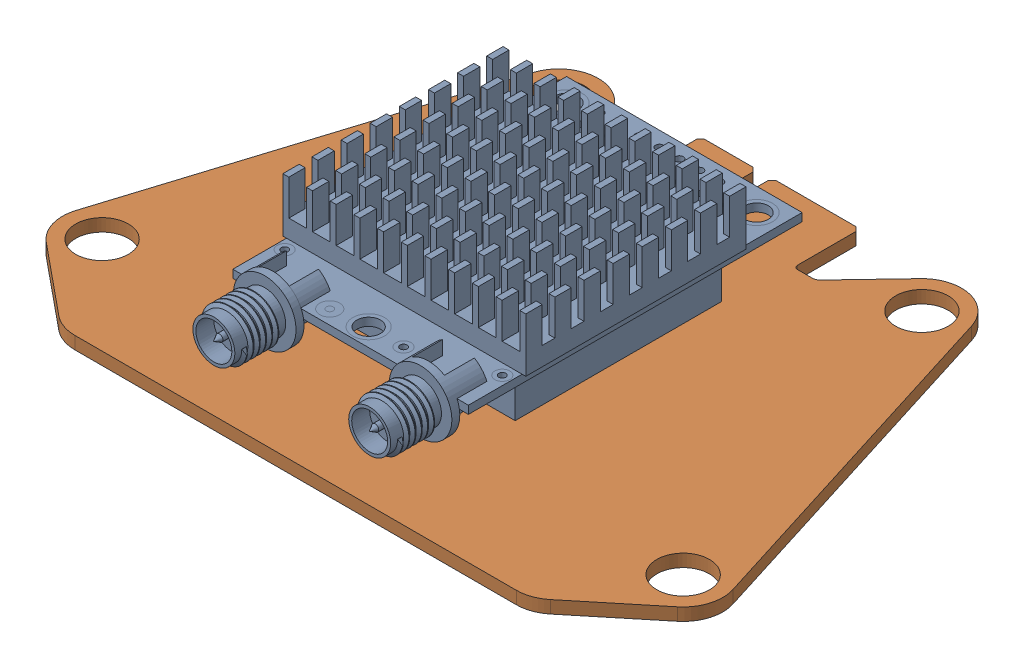
SolidWorks assembly rfd_board1, configuration Default. Lengths in mm.
Overall size (84.1 18.84 62.22).
4 component instances, 4 part files, 11 mates.
Components (placement in the parent):
- RFD 900+-1: RFD 900+ [Default] at (0 11.156 -2.7892) x (-1 0 0) z (0 0 1) size (30.94 13.23 49.99)
- PinHeader_2x08_P2.54mm_Vertical-1: PinHeader_2x08_P2.54mm_Vertical [Default] at (8.89 10.14 -19.985) x (0 0 -1) z (0 -1 0) (suppressed, hidden)
- PinSocket_2x08_P2.54mm_Vertical-1: PinSocket_2x08_P2.54mm_Vertical [Default] at (-8.89 0.6 -22.525) x (0 0 -1) z (0 1 0) (suppressed, hidden)
- board-1: board [Default] at origin size (84.1 1.6 61.73)
Mates (geometry in assembly coordinates):
- Distance3: distance = 7 mm aligned: plane of RFD 900+-1 through (-15 10.14 18.07) normal (0 0 1); plane of board-1 through (0 -0.8 25.07) normal (0 0 1)
- Coincident4: coincident: point of RFD 900+-1
- Coincident28: coincident: unknown of board-1
- Coincident19: coincident anti-aligned: plane of RFD 900+-1 through (0 10.14 -2.7892) normal (0 -1 0); plane of PinHeader_2x08_P2.54mm_Vertical-1 through (0 10.14 -21.255) normal (0 1 0)
- Distance5: distance = 1.585 mm aligned: plane of PinHeader_2x08_P2.54mm_Vertical-1 through (-9.21 13.14 -22.845) normal (0 0 -1); plane of RFD 900+-1 through (-15 10.14 -24.43) normal (0 0 -1)
- Distance7: distance = 0 mm anti-aligned: plane of PinHeader_2x08_P2.54mm_Vertical-1 through (0 7.6 -21.255) normal (0 -1 0); plane of PinSocket_2x08_P2.54mm_Vertical-1 through (10.16 7.6 -23.795) normal (0 1 0)
- Coincident23: coincident aligned: plane of PinHeader_2x08_P2.54mm_Vertical-1 through (-10.16 10.14 -18.969) normal (-1 0 0); plane of PinSocket_2x08_P2.54mm_Vertical-1 through (-10.16 0.6 -23.795) normal (-1 0 0)
- Coincident24: coincident aligned: plane of PinHeader_2x08_P2.54mm_Vertical-1 through (-4.826 10.14 -23.795) normal (0 0 -1); plane of PinSocket_2x08_P2.54mm_Vertical-1 through (10.16 0.6 -23.795) normal (0 0 -1)
- Coincident25: coincident anti-aligned: plane of board-1 through (0 0.8 0) normal (0 1 0); plane of PinSocket_2x08_P2.54mm_Vertical-1 through (10.16 0.8 -22.9483) normal (0 -1 0)
- Coincident26: coincident: line of PinHeader_2x08_P2.54mm_Vertical-1 through (0 10.14 -23.541) axis (0 -1 0)
- Coincident27: coordinate: unknown of board-1
